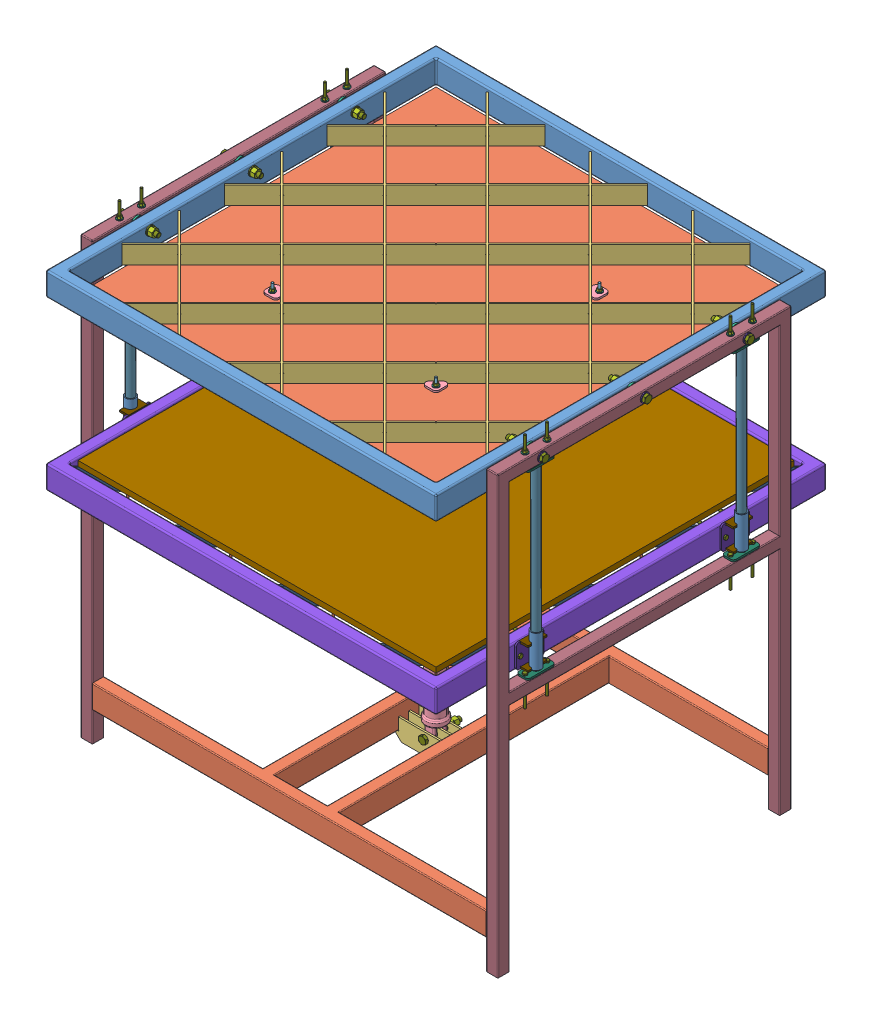
SolidWorks assembly CoolingPress, configuration Default. Lengths in mm.
Overall size (1448 1539 1330).
188 component instances, 26 part files, 122 mates.
Components (placement in the parent):
- Pressing plate upper-1: Pressing plate upper [Default] at origin size (1330 88 1330)
  - Plate frame upper-1: Plate frame upper [Default] at origin size (1330 80 1330)
  - Pressing plate upper-1: Pressing plate upper [Default] x (-1 0 0) z (0 -1 0) size (1220 1220 18)
  - Support structure upper-1: Support structure upper [Default] at origin size (1250 60 1250)
    - Support structure upper-1: Support structure upper [Default] at (0 10 0) size (1250 60 1250)
    - Support structure upper-2: Support structure upper [Default] at (0 70 0) x (-1 0 0) z (0 0 1) size (1250 60 1250)
  - Plywood mount tab-1: Plywood mount tab [Default] at (0 70 0) x (1 0 0) z (0 1 0) size (46.67 46.67 6)
  - Plywood mount tab-2: Plywood mount tab [Default] at (0 70 0) x (0 0 1) z (0 1 0) size (46.67 46.67 6)
  - Plywood mount tab-3: Plywood mount tab [Default] at (0 70 0) x (-1 0 0) z (0 1 0) size (46.67 46.67 6)
  - Plywood mount tab-4: Plywood mount tab [Default] at (0 70 0) x (0 0 -1) z (0 1 0) size (46.67 46.67 6)
  - socket countersunk head screw_iso-1: socket countersunk head screw_iso [ISO 10642 - M8 x 50 - 28N] at (278.7635 -6.96 278.7635) x (0 1 0) z (0 0 1) size (50 15.24 15.24)
  - plain washer 10669 type nl_iso-1: plain washer 10669 type nl_iso [ISO 10669-8.8-N] at (278.7635 17 278.7635) x (0 1 0) z (0 0 1) size (2 20 20)
  - hex nut gradec_iso-1: hex nut gradec_iso [ISO - 4034 - M8 - N] at (278.7635 26.9 278.7635) x (1 0 0) z (0 1 0) size (13 15.01 7.9)
  - plain washer 10669 type nl_iso-2: plain washer 10669 type nl_iso [ISO 10669-8.8-N] at (-278.7635 17 278.7635) x (0 1 0) z (-1 0 0) size (2 20 20)
  - plain washer 10669 type nl_iso-3: plain washer 10669 type nl_iso [ISO 10669-8.8-N] at (-278.7635 17 -278.7635) x (0 1 0) z (0 0 -1) size (2 20 20)
  - plain washer 10669 type nl_iso-4: plain washer 10669 type nl_iso [ISO 10669-8.8-N] at (278.7635 17 -278.7635) x (0 1 0) z (1 0 0) size (2 20 20)
  - hex nut gradec_iso-2: hex nut gradec_iso [ISO - 4034 - M8 - N] at (-278.7635 26.9 278.7635) x (0 0 1) z (0 1 0) size (13 15.01 7.9)
  - hex nut gradec_iso-3: hex nut gradec_iso [ISO - 4034 - M8 - N] at (-278.7635 26.9 -278.7635) x (-1 0 0) z (0 1 0) size (13 15.01 7.9)
  - hex nut gradec_iso-4: hex nut gradec_iso [ISO - 4034 - M8 - N] at (278.7635 26.9 -278.7635) x (0 0 -1) z (0 1 0) size (13 15.01 7.9)
  - socket countersunk head screw_iso-2: socket countersunk head screw_iso [ISO 10642 - M8 x 50 - 28N] at (-278.7635 -6.96 278.7635) x (0 1 0) z (-1 0 0) size (50 15.24 15.24)
  - socket countersunk head screw_iso-3: socket countersunk head screw_iso [ISO 10642 - M8 x 50 - 28N] at (-278.7635 -6.96 -278.7635) x (0 1 0) z (0 0 -1) size (50 15.24 15.24)
  - socket countersunk head screw_iso-4: socket countersunk head screw_iso [ISO 10642 - M8 x 50 - 28N] at (278.7635 -6.96 -278.7635) x (0 1 0) z (1 0 0) size (50 15.24 15.24)
- Pressing plate lower-1: Pressing plate lower [Default] at (0 -490 0) x (-1 0 0) z (0 0 1) size (1330 195 1330)
  - Plate frame lower-1: Plate frame lower [Default] at origin size (1330 80 1330)
  - Pressing plate lower-1: Pressing plate lower [Default] x (-1 0 0) z (0 -1 0) size (1220 1220 18)
  - Support structure lower-1: Support structure lower [Default] at (0 -250.8864 0) x (-1 0 0) z (0 0 1) size (1250 177 1250)
    - Support structure lower a-1: Support structure lower a [Default] at (0 -260.8864 0) x (-1 0 0) z (0 0 1) size (1250 140 1250)
    - Support structure lower b-1: Support structure lower b [Default] at (0 -260.8864 0) x (0 0 -1) z (-1 0 0) size (1250 140 1250)
    - Jack mount-1: Jack mount [Default] at (-15.5563 -260.8864 -15.5563) x (-0.707107 0 0.707107) z (0.707107 0 0.707107) size (75 77 6)
    - Jack mount-2: Jack mount [Default] at (15.5563 -260.8864 15.5563) x (0.707107 0 -0.707107) z (-0.707107 0 -0.707107) size (75 77 6)
- Side frame asm-1: Side frame asm [Default] at (148.9643 90.3004 -178.1954) size (46 1539 1000)
  - Side frame sub asm-1: Side frame sub asm [Default] at (-148.9643 -90.3004 178.1954) size (40 1539 1000)
    - Side frame-1: Side frame [Default] at (665 0 0) x (0 0 -1) z (1 0 0) size (1000 1485 40)
    - Slider rod-1: Slider rod [Default] at (343.5 40 -330) x (1 0 0) z (0 -1 0) size (27 27 620)
    - Slider rod plate-1: Slider rod plate [Default] at (711 -574 -2.5) x (0 0 -1) z (0 -1 0) size (95 40 6)
    - Slider rod plate-2: Slider rod plate [Default] at (711 40 -2.5) x (0 0 -1) z (0 -1 0) size (95 40 6)
    - Slider rod plate-3: Slider rod plate [Default] at (711 -580 2.5) x (0 0 1) z (0 1 0) size (95 40 6)
    - Slider rod plate-4: Slider rod plate [Default] at (711 34 2.5) x (0 0 1) z (0 1 0) size (95 40 6)
    - Slider rod-2: Slider rod [Default] at (343.5 -580 330) x (1 0 0) z (0 1 0) size (27 27 620)
    - hex bolt gradeab_iso-1: hex bolt gradeab_iso [ISO 4014 - M8 x 100 x 100-N] at (691 28.7 -312.5) x (0 1 0) z (0 0 1) size (105.3 15.01 13)
    - hex bolt gradeab_iso-2: hex bolt gradeab_iso [ISO 4014 - M8 x 100 x 100-N] at (691 28.7 -387.5) x (0 1 0) z (0 0 1) size (105.3 15.01 13)
    - hex bolt gradeab_iso-3: hex bolt gradeab_iso [ISO 4014 - M8 x 100 x 100-N] at (691 -568.7 -312.5) x (0 -1 0) z (0 0 1) size (105.3 15.01 13)
    - hex bolt gradeab_iso-4: hex bolt gradeab_iso [ISO 4014 - M8 x 100 x 100-N] at (691 -568.7 -387.5) x (0 -1 0) z (0 0 1) size (105.3 15.01 13)
    - plain washer 10669 type nl_iso-1: plain washer 10669 type nl_iso [ISO 10669-8.8-N] at (691 80 -312.5) x (0 1 0) z (0 0 1) size (2 20 20)
    - plain washer 10669 type nl_iso-2: plain washer 10669 type nl_iso [ISO 10669-8.8-N] at (691 80 -387.5) x (0 1 0) z (0 0 1) size (2 20 20)
    - plain washer 10669 type nl_iso-3: plain washer 10669 type nl_iso [ISO 10669-8.8-N] at (691 -620 -312.5) x (0 -1 0) z (0 0 1) size (2 20 20)
    - plain washer 10669 type nl_iso-4: plain washer 10669 type nl_iso [ISO 10669-8.8-N] at (691 -620 -387.5) x (0 -1 0) z (0 0 1) size (2 20 20)
    - hex nut gradec_iso-1: hex nut gradec_iso [ISO - 4034 - M8 - N] at (691 -629.9 -387.5) x (1 0 0) z (0 -1 0) size (13 15.01 7.9)
    - hex nut gradec_iso-2: hex nut gradec_iso [ISO - 4034 - M8 - N] at (691 -629.9 -312.5) x (1 0 0) z (0 -1 0) size (13 15.01 7.9)
    - hex nut gradec_iso-3: hex nut gradec_iso [ISO - 4034 - M8 - N] at (691 89.9 -312.5) x (1 0 0) z (0 1 0) size (13 15.01 7.9)
    - hex nut gradec_iso-4: hex nut gradec_iso [ISO - 4034 - M8 - N] at (691 89.9 -387.5) x (1 0 0) z (0 1 0) size (13 15.01 7.9)
    - hex bolt gradeab_iso-5: hex bolt gradeab_iso [ISO 4014 - M8 x 100 x 100-N] at (691 28.7 387.5) x (0 1 0) z (0 0 1) size (105.3 15.01 13)
    - hex bolt gradeab_iso-6: hex bolt gradeab_iso [ISO 4014 - M8 x 100 x 100-N] at (691 -568.7 312.5) x (0 -1 0) z (0 0 1) size (105.3 15.01 13)
    - hex bolt gradeab_iso-7: hex bolt gradeab_iso [ISO 4014 - M8 x 100 x 100-N] at (691 -568.7 387.5) x (0 -1 0) z (0 0 1) size (105.3 15.01 13)
    - plain washer 10669 type nl_iso-5: plain washer 10669 type nl_iso [ISO 10669-8.8-N] at (691 80 312.5) x (0 1 0) z (0 0 1) size (2 20 20)
    - plain washer 10669 type nl_iso-6: plain washer 10669 type nl_iso [ISO 10669-8.8-N] at (691 80 387.5) x (0 1 0) z (0 0 1) size (2 20 20)
    - plain washer 10669 type nl_iso-7: plain washer 10669 type nl_iso [ISO 10669-8.8-N] at (691 -620 312.5) x (0 -1 0) z (0 0 1) size (2 20 20)
    - plain washer 10669 type nl_iso-8: plain washer 10669 type nl_iso [ISO 10669-8.8-N] at (691 -620 387.5) x (0 -1 0) z (0 0 1) size (2 20 20)
    - hex nut gradec_iso-5: hex nut gradec_iso [ISO - 4034 - M8 - N] at (691 -622 387.5) x (1 0 0) z (0 1 0) size (13 15.01 7.9)
    - hex nut gradec_iso-6: hex nut gradec_iso [ISO - 4034 - M8 - N] at (691 -622 312.5) x (1 0 0) z (0 1 0) size (13 15.01 7.9)
    - hex nut gradec_iso-7: hex nut gradec_iso [ISO - 4034 - M8 - N] at (691 82 387.5) x (1 0 0) z (0 -1 0) size (13 15.01 7.9)
    - hex bolt gradeab_iso-8: hex bolt gradeab_iso [ISO 4014 - M8 x 100 x 100-N] at (691 28.7 312.5) x (0 1 0) z (0 0 1) size (105.3 15.01 13)
    - hex nut gradec_iso-8: hex nut gradec_iso [ISO - 4034 - M8 - N] at (691 82 312.5) x (1 0 0) z (0 -1 0) size (13 15.01 7.9)
  - Slider bracket-1: Slider bracket [Default] at (-148.9643 -510.7439 178.1954) size (43 110 95)
    - Guide plate coldpress-1: Guide plate coldpress [Default] at (671 -169.5566 -2.5) x (0 0 1) z (-1 0 0) size (95 80 6)
    - Guide bracket-1: Guide bracket [Default] at (665 -169.5566 -697.5) x (0 0 -1) z (1 0 0) size (65 80 31)
    - Slider tube-1: Slider tube [Default] at (665 -149.5566 -697.5) x (0 0 1) z (0 -1 0) size (34 34 110)
  - Slider bracket-2: Slider bracket [Default] at (-148.9643 -510.7439 878.1954) size (43 110 95)
    - Guide plate coldpress-1: Guide plate coldpress [Default] at (671 -169.5566 -2.5) x (0 0 1) z (-1 0 0) size (95 80 6)
    - Guide bracket-1: Guide bracket [Default] at (665 -169.5566 -697.5) x (0 0 -1) z (1 0 0) size (65 80 31)
    - Slider tube-1: Slider tube [Default] at (665 -149.5566 -697.5) x (0 0 1) z (0 -1 0) size (34 34 110)
- Side frame asm-2: Side frame asm [Default] at (-148.9643 90.3004 178.1954) x (-1 0 0) z (0 0 -1) size (46 1539 1000)
  - Side frame sub asm-1: Side frame sub asm [Default] at (-148.9643 -90.3004 178.1954) size (40 1539 1000)
    - Side frame-1: Side frame [Default] at (665 0 0) x (0 0 -1) z (1 0 0) size (1000 1485 40)
    - Slider rod-1: Slider rod [Default] at (343.5 40 -330) x (1 0 0) z (0 -1 0) size (27 27 620)
    - Slider rod plate-1: Slider rod plate [Default] at (711 -574 -2.5) x (0 0 -1) z (0 -1 0) size (95 40 6)
    - Slider rod plate-2: Slider rod plate [Default] at (711 40 -2.5) x (0 0 -1) z (0 -1 0) size (95 40 6)
    - Slider rod plate-3: Slider rod plate [Default] at (711 -580 2.5) x (0 0 1) z (0 1 0) size (95 40 6)
    - Slider rod plate-4: Slider rod plate [Default] at (711 34 2.5) x (0 0 1) z (0 1 0) size (95 40 6)
    - Slider rod-2: Slider rod [Default] at (343.5 -580 330) x (1 0 0) z (0 1 0) size (27 27 620)
    - hex bolt gradeab_iso-1: hex bolt gradeab_iso [ISO 4014 - M8 x 100 x 100-N] at (691 28.7 -312.5) x (0 1 0) z (0 0 1) size (105.3 15.01 13)
    - hex bolt gradeab_iso-2: hex bolt gradeab_iso [ISO 4014 - M8 x 100 x 100-N] at (691 28.7 -387.5) x (0 1 0) z (0 0 1) size (105.3 15.01 13)
    - hex bolt gradeab_iso-3: hex bolt gradeab_iso [ISO 4014 - M8 x 100 x 100-N] at (691 -568.7 -312.5) x (0 -1 0) z (0 0 1) size (105.3 15.01 13)
    - hex bolt gradeab_iso-4: hex bolt gradeab_iso [ISO 4014 - M8 x 100 x 100-N] at (691 -568.7 -387.5) x (0 -1 0) z (0 0 1) size (105.3 15.01 13)
    - plain washer 10669 type nl_iso-1: plain washer 10669 type nl_iso [ISO 10669-8.8-N] at (691 80 -312.5) x (0 1 0) z (0 0 1) size (2 20 20)
    - plain washer 10669 type nl_iso-2: plain washer 10669 type nl_iso [ISO 10669-8.8-N] at (691 80 -387.5) x (0 1 0) z (0 0 1) size (2 20 20)
    - plain washer 10669 type nl_iso-3: plain washer 10669 type nl_iso [ISO 10669-8.8-N] at (691 -620 -312.5) x (0 -1 0) z (0 0 1) size (2 20 20)
    - plain washer 10669 type nl_iso-4: plain washer 10669 type nl_iso [ISO 10669-8.8-N] at (691 -620 -387.5) x (0 -1 0) z (0 0 1) size (2 20 20)
    - hex nut gradec_iso-1: hex nut gradec_iso [ISO - 4034 - M8 - N] at (691 -629.9 -387.5) x (1 0 0) z (0 -1 0) size (13 15.01 7.9)
    - hex nut gradec_iso-2: hex nut gradec_iso [ISO - 4034 - M8 - N] at (691 -629.9 -312.5) x (1 0 0) z (0 -1 0) size (13 15.01 7.9)
    - hex nut gradec_iso-3: hex nut gradec_iso [ISO - 4034 - M8 - N] at (691 89.9 -312.5) x (1 0 0) z (0 1 0) size (13 15.01 7.9)
    - hex nut gradec_iso-4: hex nut gradec_iso [ISO - 4034 - M8 - N] at (691 89.9 -387.5) x (1 0 0) z (0 1 0) size (13 15.01 7.9)
    - hex bolt gradeab_iso-5: hex bolt gradeab_iso [ISO 4014 - M8 x 100 x 100-N] at (691 28.7 387.5) x (0 1 0) z (0 0 1) size (105.3 15.01 13)
    - hex bolt gradeab_iso-6: hex bolt gradeab_iso [ISO 4014 - M8 x 100 x 100-N] at (691 -568.7 312.5) x (0 -1 0) z (0 0 1) size (105.3 15.01 13)
    - hex bolt gradeab_iso-7: hex bolt gradeab_iso [ISO 4014 - M8 x 100 x 100-N] at (691 -568.7 387.5) x (0 -1 0) z (0 0 1) size (105.3 15.01 13)
    - plain washer 10669 type nl_iso-5: plain washer 10669 type nl_iso [ISO 10669-8.8-N] at (691 80 312.5) x (0 1 0) z (0 0 1) size (2 20 20)
    - plain washer 10669 type nl_iso-6: plain washer 10669 type nl_iso [ISO 10669-8.8-N] at (691 80 387.5) x (0 1 0) z (0 0 1) size (2 20 20)
    - plain washer 10669 type nl_iso-7: plain washer 10669 type nl_iso [ISO 10669-8.8-N] at (691 -620 312.5) x (0 -1 0) z (0 0 1) size (2 20 20)
    - plain washer 10669 type nl_iso-8: plain washer 10669 type nl_iso [ISO 10669-8.8-N] at (691 -620 387.5) x (0 -1 0) z (0 0 1) size (2 20 20)
    - hex nut gradec_iso-5: hex nut gradec_iso [ISO - 4034 - M8 - N] at (691 -622 387.5) x (1 0 0) z (0 1 0) size (13 15.01 7.9)
    - hex nut gradec_iso-6: hex nut gradec_iso [ISO - 4034 - M8 - N] at (691 -622 312.5) x (1 0 0) z (0 1 0) size (13 15.01 7.9)
    - hex nut gradec_iso-7: hex nut gradec_iso [ISO - 4034 - M8 - N] at (691 82 387.5) x (1 0 0) z (0 -1 0) size (13 15.01 7.9)
    - hex bolt gradeab_iso-8: hex bolt gradeab_iso [ISO 4014 - M8 x 100 x 100-N] at (691 28.7 312.5) x (0 1 0) z (0 0 1) size (105.3 15.01 13)
    - hex nut gradec_iso-8: hex nut gradec_iso [ISO - 4034 - M8 - N] at (691 82 312.5) x (1 0 0) z (0 -1 0) size (13 15.01 7.9)
  - Slider bracket-1: Slider bracket [Default] at (-148.9643 -510.7439 178.1954) size (43 110 95)
    - Guide plate coldpress-1: Guide plate coldpress [Default] at (671 -169.5566 -2.5) x (0 0 1) z (-1 0 0) size (95 80 6)
    - Guide bracket-1: Guide bracket [Default] at (665 -169.5566 -697.5) x (0 0 -1) z (1 0 0) size (65 80 31)
    - Slider tube-1: Slider tube [Default] at (665 -149.5566 -697.5) x (0 0 1) z (0 -1 0) size (34 34 110)
  - Slider bracket-2: Slider bracket [Default] at (-148.9643 -510.7439 878.1954) size (43 110 95)
    - Guide plate coldpress-1: Guide plate coldpress [Default] at (671 -169.5566 -2.5) x (0 0 1) z (-1 0 0) size (95 80 6)
    - Guide bracket-1: Guide bracket [Default] at (665 -169.5566 -697.5) x (0 0 -1) z (1 0 0) size (65 80 31)
    - Slider tube-1: Slider tube [Default] at (665 -149.5566 -697.5) x (0 0 1) z (0 -1 0) size (34 34 110)
- Bottom frame asm-1: Bottom frame asm [Default] at (-144.5589 173.4267 15.9564) size (1342 110 1000)
  - Part2-1: Part2 [Default] at (144.5589 -1478.4267 -15.9564) x (-1 0 0) z (0 -1 0) size (1342 1000 80)
  - Jack plate lower-1: Jack plate lower [Default] at origin size (200 70 6)
  - Jack plate lower-2: Jack plate lower [Default] at (0 0 35) size (200 70 6)
  - Jack plate lower-4: Jack plate lower [Default] at (0 0 -35) size (200 70 6)
- Jack asm-2: Jack asm [Default] at (0 -1250 0) x (0 0 1) z (-1 0 0) size (71.65 655 71.65) (flexible)
  - Cylinder-1: Cylinder [Default] at origin size (71.65 615 71.65)
  - Jack rod-1: Jack rod [Default] at (-0.0001 55 -0.0001) x (0.707107 0 0.707107) z (-0.707107 0 0.707107) size (28 550 28)
- Spacer-4: Spacer [Default] at (-671 0 0) x (0 0 -1) z (1 0 0) size (40 40 6)
- Spacer-5: Spacer [Default] at (-665 0 -350) x (0 0 1) z (-1 0 0) size (40 40 6)
- Spacer-6: Spacer [Default] at (-671 0 700) x (0 0 -1) z (1 0 0) size (40 40 6)
- Spacer-1: Spacer [Default] at (665 0 0) x (0 0 -1) z (1 0 0) size (40 40 6)
- Spacer-2: Spacer [Default] at (671 0 -350) x (0 0 1) z (-1 0 0) size (40 40 6)
- Spacer-3: Spacer [Default] at (665 0 700) x (0 0 -1) z (1 0 0) size (40 40 6)
- hex bolt gradeab_iso-3: hex bolt gradeab_iso [ISO 4014 - M8 x 100 x 100-N] at (676.3 -530 -314.5) x (-1 0 0) z (0 0.924225 0.381849) size (105.3 15.01 13)
- hex bolt gradeab_iso-4: hex bolt gradeab_iso [ISO 4014 - M8 x 100 x 100-N] at (676.3 -530 -385.5) x (-1 0 0) z (0 0.924225 0.381849) size (105.3 15.01 13)
- hex bolt gradeab_iso-8: hex bolt gradeab_iso [ISO 4014 - M16 x 120 x 38-N] at (724 60 -350) x (-1 0 0) z (0 0.981514 -0.191391) size (130 27.71 24)
- hex bolt gradeab_iso-9: hex bolt gradeab_iso [ISO 4014 - M16 x 120 x 38-N] at (724 60 0) x (-1 0 0) z (0 -0.958722 -0.284344) size (130 27.71 24)
- hex bolt gradeab_iso-10: hex bolt gradeab_iso [ISO 4014 - M16 x 120 x 38-N] at (0 -1285 48) x (0 0 -1) z (1 0 0) size (130 27.71 24)
- hex bolt gradeab_iso-11: hex bolt gradeab_iso [ISO 4014 - M16 x 120 x 38-N] at (22.6275 -665 22.6274) x (-0.707107 0 -0.707107) z (0.707107 0 -0.707107) size (130 27.71 24)
- plain washer 10669 type nl_iso-5: plain washer 10669 type nl_iso [ISO 10669-8.8-N] at (625 -530 -314.5) x (-1 0 0) z (0 0.924225 0.381849) size (2 20 20)
- plain washer 10669 type nl_iso-6: plain washer 10669 type nl_iso [ISO 10669-8.8-N] at (625 -530 -385.5) x (-1 0 0) z (0 0.924225 0.381849) size (2 20 20)
- plain washer normal grade a_iso-1: plain washer normal grade a_iso [Washer ISO 7089 - 16] at (625 60 -350) size (3 30 30)
- plain washer normal grade a_iso-2: plain washer normal grade a_iso [Washer ISO 7089 - 16] at (625 60 0) size (3 30 30)
- hex nut gradec_iso-1: hex nut gradec_iso [ISO - 4034 - M16 - N] at (606.1 60 -350) x (0 0 1) z (-1 0 0) size (24 27.71 15.9)
- hex nut gradec_iso-2: hex nut gradec_iso [ISO - 4034 - M16 - N] at (606.1 60 0) x (0 0 1) z (-1 0 0) size (24 27.71 15.9)
- hex nut gradec_iso-3: hex nut gradec_iso [ISO - 4034 - M16 - N] at (-26.7994 -665 -26.7993) x (-0.707107 0 0.707107) z (-0.707107 0 -0.707107) size (24 27.71 15.9)
- hex nut gradec_iso-4: hex nut gradec_iso [ISO - 4034 - M16 - N] at (-38.0424 -665 -38.0423) x (-0.707107 0 0.707107) z (-0.707107 0 -0.707107) size (24 27.71 15.9)
- hex nut gradec_iso-5: hex nut gradec_iso [ISO - 4034 - M16 - N] at (0 -1285 -53.9) x (0.923728 0.383049 0) z (0 0 -1) size (24 27.71 15.9)
- hex nut gradec_iso-6: hex nut gradec_iso [ISO - 4034 - M16 - N] at (0 -1285 -69.8) x (0.923728 0.383049 0) z (0 0 -1) size (24 27.71 15.9)
- hex nut gradec_iso-11: hex nut gradec_iso [ISO - 4034 - M8 - N] at (615.1 -530 -314.5) x (0 0 1) z (-1 0 0) size (13 15.01 7.9)
- hex nut gradec_iso-12: hex nut gradec_iso [ISO - 4034 - M8 - N] at (615.1 -530 -385.5) x (0 0 1) z (-1 0 0) size (13 15.01 7.9)
- hex nut gradec_iso-13: hex nut gradec_iso [ISO - 4034 - M8 - N] at (607.2 -530 -314.5) x (0 0 1) z (-1 0 0) size (13 15.01 7.9)
- hex nut gradec_iso-14: hex nut gradec_iso [ISO - 4034 - M8 - N] at (607.2 -530 -385.5) x (0 0 1) z (-1 0 0) size (13 15.01 7.9)
- plain washer normal grade c_iso-1: plain washer normal grade c_iso [Washer ISO 7091 - 16] at (711 60 -350) x (-1 0 0) z (0 0.924225 0.381849) size (3 30 30)
- plain washer normal grade c_iso-2: plain washer normal grade c_iso [Washer ISO 7091 - 16] at (711 60 0) x (-1 0 0) z (0 0.924225 0.381849) size (3 30 30)
- hex bolt gradeab_iso-13: hex bolt gradeab_iso [ISO 4014 - M16 x 120 x 38-N] at (724 60 350) x (-1 0 0) z (0 -0.981514 -0.191391) size (130 27.71 24)
- hex nut gradec_iso-15: hex nut gradec_iso [ISO - 4034 - M16 - N] at (622 60 350) x (0 0 -1) z (1 0 0) size (24 27.71 15.9)
- plain washer normal grade a_iso-3: plain washer normal grade a_iso [Washer ISO 7089 - 16] at (625 60 350) size (3 30 30)
- hex bolt gradeab_iso-14: hex bolt gradeab_iso [ISO 4014 - M16 x 120 x 38-N] at (-724 60 -350) x (1 0 0) z (0 -0.981514 0.191391) size (130 27.71 24)
- hex nut gradec_iso-16: hex nut gradec_iso [ISO - 4034 - M16 - N] at (-622 60 -350) x (0 0 1) z (-1 0 0) size (24 27.71 15.9)
- plain washer normal grade a_iso-4: plain washer normal grade a_iso [Washer ISO 7089 - 16] at (-625 60 -350) x (-1 0 0) z (0 0 -1) size (3 30 30)
- hex bolt gradeab_iso-15: hex bolt gradeab_iso [ISO 4014 - M16 x 120 x 38-N] at (-724 60 350) x (1 0 0) z (0 0.981514 0.191391) size (130 27.71 24)
- hex nut gradec_iso-17: hex nut gradec_iso [ISO - 4034 - M16 - N] at (-606.1 60 350) x (0 0 -1) z (1 0 0) size (24 27.71 15.9)
- plain washer normal grade a_iso-5: plain washer normal grade a_iso [Washer ISO 7089 - 16] at (-625 60 350) x (-1 0 0) z (0 0 -1) size (3 30 30)
- plain washer normal grade a_iso-6: plain washer normal grade a_iso [Washer ISO 7089 - 16] at (-625 60 0) x (-1 0 0) z (0 0 -1) size (3 30 30)
- hex bolt gradeab_iso-16: hex bolt gradeab_iso [ISO 4014 - M16 x 120 x 38-N] at (-724 60 0) x (1 0 0) z (0 0.958722 0.284344) size (130 27.71 24)
- hex nut gradec_iso-18: hex nut gradec_iso [ISO - 4034 - M16 - N] at (-622 60 0) x (0 0 1) z (-1 0 0) size (24 27.71 15.9)
- hex bolt gradeab_iso-17: hex bolt gradeab_iso [ISO 4014 - M8 x 100 x 100-N] at (676.3 -530 314.5) x (-1 0 0) z (0 -0.924225 0.381849) size (105.3 15.01 13)
- hex nut gradec_iso-19: hex nut gradec_iso [ISO - 4034 - M8 - N] at (615.1 -530 314.5) x (0 0 -1) z (1 0 0) size (13 15.01 7.9)
- hex nut gradec_iso-20: hex nut gradec_iso [ISO - 4034 - M8 - N] at (623 -530 314.5) x (0 0 -1) z (1 0 0) size (13 15.01 7.9)
- plain washer 10669 type nl_iso-7: plain washer 10669 type nl_iso [ISO 10669-8.8-N] at (625 -530 314.5) x (-1 0 0) z (0 -0.924225 0.381849) size (2 20 20)
- hex bolt gradeab_iso-18: hex bolt gradeab_iso [ISO 4014 - M8 x 100 x 100-N] at (676.3 -530 385.5) x (-1 0 0) z (0 -0.924225 0.381849) size (105.3 15.01 13)
- hex nut gradec_iso-21: hex nut gradec_iso [ISO - 4034 - M8 - N] at (615.1 -530 385.5) x (0 0 -1) z (1 0 0) size (13 15.01 7.9)
- hex nut gradec_iso-22: hex nut gradec_iso [ISO - 4034 - M8 - N] at (623 -530 385.5) x (0 0 -1) z (1 0 0) size (13 15.01 7.9)
- plain washer 10669 type nl_iso-8: plain washer 10669 type nl_iso [ISO 10669-8.8-N] at (625 -530 385.5) x (-1 0 0) z (0 -0.924225 0.381849) size (2 20 20)
- hex bolt gradeab_iso-19: hex bolt gradeab_iso [ISO 4014 - M8 x 100 x 100-N] at (-676.3 -530 -314.5) x (1 0 0) z (0 -0.924225 -0.381849) size (105.3 15.01 13)
- hex nut gradec_iso-23: hex nut gradec_iso [ISO - 4034 - M8 - N] at (-615.1 -530 -314.5) x (0 0 1) z (-1 0 0) size (13 15.01 7.9)
- hex nut gradec_iso-24: hex nut gradec_iso [ISO - 4034 - M8 - N] at (-623 -530 -314.5) x (0 0 1) z (-1 0 0) size (13 15.01 7.9)
- plain washer 10669 type nl_iso-9: plain washer 10669 type nl_iso [ISO 10669-8.8-N] at (-625 -530 -314.5) x (1 0 0) z (0 -0.924225 -0.381849) size (2 20 20)
- hex bolt gradeab_iso-20: hex bolt gradeab_iso [ISO 4014 - M8 x 100 x 100-N] at (-676.3 -530 -385.5) x (1 0 0) z (0 -0.924225 -0.381849) size (105.3 15.01 13)
- hex nut gradec_iso-25: hex nut gradec_iso [ISO - 4034 - M8 - N] at (-615.1 -530 -385.5) x (0 0 1) z (-1 0 0) size (13 15.01 7.9)
- hex nut gradec_iso-26: hex nut gradec_iso [ISO - 4034 - M8 - N] at (-623 -530 -385.5) x (0 0 1) z (-1 0 0) size (13 15.01 7.9)
- plain washer 10669 type nl_iso-10: plain washer 10669 type nl_iso [ISO 10669-8.8-N] at (-625 -530 -385.5) x (1 0 0) z (0 -0.924225 -0.381849) size (2 20 20)
- hex bolt gradeab_iso-21: hex bolt gradeab_iso [ISO 4014 - M8 x 100 x 100-N] at (-676.3 -530 385.5) x (1 0 0) z (0 0.924225 -0.381849) size (105.3 15.01 13)
- hex nut gradec_iso-27: hex nut gradec_iso [ISO - 4034 - M8 - N] at (-607.2 -530 385.5) x (0 0 -1) z (1 0 0) size (13 15.01 7.9)
- hex nut gradec_iso-28: hex nut gradec_iso [ISO - 4034 - M8 - N] at (-615.1 -530 385.5) x (0 0 -1) z (1 0 0) size (13 15.01 7.9)
- plain washer 10669 type nl_iso-11: plain washer 10669 type nl_iso [ISO 10669-8.8-N] at (-625 -530 385.5) x (1 0 0) z (0 0.924225 -0.381849) size (2 20 20)
- hex bolt gradeab_iso-22: hex bolt gradeab_iso [ISO 4014 - M8 x 100 x 100-N] at (-676.3 -530 314.5) x (1 0 0) z (0 0.924225 -0.381849) size (105.3 15.01 13)
- hex nut gradec_iso-29: hex nut gradec_iso [ISO - 4034 - M8 - N] at (-607.2 -530 314.5) x (0 0 -1) z (1 0 0) size (13 15.01 7.9)
- hex nut gradec_iso-30: hex nut gradec_iso [ISO - 4034 - M8 - N] at (-615.1 -530 314.5) x (0 0 -1) z (1 0 0) size (13 15.01 7.9)
- plain washer 10669 type nl_iso-12: plain washer 10669 type nl_iso [ISO 10669-8.8-N] at (-625 -530 314.5) x (1 0 0) z (0 0.924225 -0.381849) size (2 20 20)
- plain washer normal grade c_iso-3: plain washer normal grade c_iso [Washer ISO 7091 - 16] at (711 60 350) x (-1 0 0) z (0 -0.924225 0.381849) size (3 30 30)
- plain washer normal grade c_iso-4: plain washer normal grade c_iso [Washer ISO 7091 - 16] at (-711 60 350) x (1 0 0) z (0 0.924225 -0.381849) size (3 30 30)
- plain washer normal grade c_iso-5: plain washer normal grade c_iso [Washer ISO 7091 - 16] at (-711 60 0) x (1 0 0) z (0 -0.924225 -0.381849) size (3 30 30)
- plain washer normal grade c_iso-6: plain washer normal grade c_iso [Washer ISO 7091 - 16] at (-711 60 -350) x (1 0 0) z (0 -0.924225 -0.381849) size (3 30 30)
Mates (geometry in assembly coordinates):
- Parallel2: parallel: plane of Pressing plate lower-1/Plate frame lower-1 through (0 -490 0) normal (0 -1 0); plane of assembly through (0 0 0) normal (0 1 0)
- Coincident3: coincident: plane of Pressing plate lower-1/Plate frame lower-1 through (0 -490 0) normal (0 0 1); plane of assembly through (0 0 0) normal (0 0 1)
- Coincident4: coincident: plane of Pressing plate lower-1/Plate frame lower-1 through (0 -490 0) normal (-1 0 0); plane of assembly through (0 0 0) normal (1 0 0)
- InPlace12: in place: plane of ? through (-671 0 460) normal (0 0 -1); plane of ? through (0 0 460) normal (0 0 -1); moOrthogonalPlaneRef_w of ? through (-671 0 460) normal (0 0 -1); plane of ? through (0 0 460) normal (0 1 0); plane of ? through (-671 0 460) normal (0 0 -1); plane of ? through (0 0 460) normal (-1 0 0); plane of ? through (-671 0 460) normal (0 0 -1); unknown of ?
- Coincident22: coincident: plane of ?; plane of ?
- Coincident23: coincident: moOrthogonalPlaneRef_w of ? through (-717 0 460) normal (0 1 0); plane of ? through (-717 0 460) normal (0 1 0)
- Coincident24: coincident: moOrthogonalPlaneRef_w of ? through (-717 0 460) normal (1 0 0); plane of ? through (-717 0 460) normal (-1 0 0)
- InPlace13: in place: plane of Pressing plate upper-1/Plate frame upper-1 through (0 0 0) normal (0 0 1); plane of Pressing plate upper-1/Plate frame upper-1 through (0 0 0) normal (0 1 0); plane of Pressing plate upper-1/Plate frame upper-1 through (0 0 0) normal (1 0 0); unknown of Pressing plate upper-1/Plate frame upper-1
- Coincident21: coincident: plane of ?; plane of assembly
- Coincident22: coincident: plane of Pressing plate upper-1/Plate frame upper-1 through (0 0 0) normal (0 1 0)
- Coincident23: coincident: plane of Pressing plate upper-1/Plate frame upper-1 through (0 0 0) normal (1 0 0)
- Parallel7: parallel: plane of Pressing plate lower-1/Support structure lower-1/Support structure lower b-1 through (0 -500 0) normal (0 -1 0); plane of assembly through (0 0 0) normal (0 1 0)
- Coincident38: coincident: plane of Pressing plate lower-1/Support structure lower-1/Support structure lower b-1 through (0 -500 0) normal (-1 0 0); plane of assembly through (0 0 0) normal (1 0 0)
- Coincident39: coincident: plane of Pressing plate lower-1/Support structure lower-1/Support structure lower b-1 through (0 -500 0) normal (0 0 -1); plane of assembly through (0 0 0) normal (0 0 1)
- Parallel8: parallel: plane of Pressing plate lower-1/Support structure lower-1/Support structure lower a-1 through (0 -500 0) normal (0 -1 0); plane of assembly through (0 0 0) normal (0 1 0)
- Coincident41: coincident: plane of Pressing plate lower-1/Support structure lower-1/Support structure lower a-1 through (0 -500 0) normal (0 0 1); plane of assembly through (0 0 0) normal (0 0 1)
- Coincident42: coincident: plane of Pressing plate lower-1/Support structure lower-1/Support structure lower a-1 through (0 -500 0) normal (-1 0 0); plane of assembly through (0 0 0) normal (1 0 0)
- Coincident53: coincident: plane of Pressing plate upper-1/Plate frame upper-1 through (0 80 0) normal (0 1 0); plane of Side frame asm-1/Side frame sub asm-1/Side frame-1 through (711 80 0) normal (0 1 0)
- Coincident54: coincident: plane of Pressing plate lower-1/Plate frame lower-1 through (665 -570 -665) normal (1 0 0); plane of Side frame asm-1/Slider bracket-1/Guide plate coldpress-1 through (665 -500 -312.5) normal (-1 0 0)
- Coincident55: coincident: plane of Pressing plate lower-1/Plate frame lower-1 through (0 -490 0) normal (0 1 0); plane of Side frame asm-1/Slider bracket-1/Guide plate coldpress-1 through (665 -490 -317.5) normal (0 1 0)
- Coincident57: coincident: plane of Pressing plate lower-1/Plate frame lower-1 through (665 -570 -665) normal (1 0 0); plane of Side frame asm-1/Slider bracket-1/Guide bracket-1 through (665 -590 -697.5) normal (-1 0 0)
- Coincident58: coincident: plane of Pressing plate lower-1/Plate frame lower-1 through (0 -490 0) normal (0 1 0); plane of Side frame asm-1/Slider bracket-1/Guide bracket-1 through (776.2763 -490 -382.5) normal (0 1 0)
- LimitDistance1: limit distance = 474 mm: plane of Pressing plate lower-1/Pressing plate lower-1 through (0 -482 0) normal (0 1 0); plane of Pressing plate upper-1/Pressing plate upper-1 through (0 -8 0) normal (0 -1 0)
- Coincident59: coincident: plane of Side frame asm-2/Side frame sub asm-1/Side frame-1 through (-711 0 500) normal (0 0 1); plane of Bottom frame asm-1/Part2-1 through (-671 -1225 500) normal (0 0 1)
- Distance3: distance = 100 mm: plane of Bottom frame asm-1/Part2-1 through (0 -1305 0) normal (0 -1 0); plane of Side frame asm-2/Side frame sub asm-1/Side frame-1 through (-711 -1405 0) normal (0 -1 0)
- Coincident61: coincident: plane of Side frame asm-1/Side frame sub asm-1/Side frame-1 through (671 0 0) normal (-1 0 0); plane of Bottom frame asm-1/Part2-1 through (671 -1225 500) normal (1 0 0)
- Coincident62: coincident: line of Jack asm-2/Cylinder-1 through (527.0226 0 -1255.0679) axis (0 0 1)
- Concentric8: concentric: cylinder of Pressing plate lower-1/Support structure lower-1/Jack mount-2 through (-64.6928 -665 -64.6929) axis (0.707107 0 0.707107) radius 9; cylinder of Jack asm-2/Jack rod-1 through (9.8996 -665 9.8994) axis (-0.707107 0 -0.707107) radius 8
- Parallel11: parallel: plane of Bottom frame asm-1/Jack plate lower-1 through (90 -1305 3) normal (0 0 1); plane of Jack asm-2/Cylinder-1 through (-17.5 -1300 -11) normal (0 0 1)
- InPlace14: in place: plane of Pressing plate upper-1/Plate frame upper-1 through (665 80 -665) normal (1 0 0); plane of ? through (665 0 0) normal (1 0 0); plane of Pressing plate upper-1/Plate frame upper-1 through (665 80 -665) normal (1 0 0); plane of ? through (665 0 0) normal (0 1 0); plane of Pressing plate upper-1/Plate frame upper-1 through (665 80 -665) normal (1 0 0); plane of ? through (665 0 0) normal (0 0 -1); plane of Pressing plate upper-1/Plate frame upper-1 through (665 80 -665) normal (1 0 0); unknown of ?
- Coincident63: coincident: plane of Pressing plate upper-1/Plate frame upper-1; plane of Spacer-1
- Coincident64: coincident: moOrthogonalPlaneRef_w of Pressing plate upper-1/Plate frame upper-1 through (665 0 0) normal (0 1 0); plane of Spacer-1 through (665 0 0) normal (0 1 0)
- Coincident65: coincident: moOrthogonalPlaneRef_w of Pressing plate upper-1/Plate frame upper-1 through (665 0 0) normal (0 0 1); plane of Spacer-1 through (665 0 0) normal (0 0 -1)
- Coincident66: coincident: plane of Pressing plate upper-1/Plate frame upper-1 through (665 80 -665) normal (1 0 0); plane of Spacer-2 through (665 60 0) normal (-1 0 0)
- Concentric9: concentric: cylinder of Side frame asm-1/Side frame sub asm-1/Side frame-1 through (671 60 0) axis (1 0 0) radius 9; cylinder of Spacer-2 through (665 60 0) axis (1 0 0) radius 8.5
- Concentric10: concentric: cylinder of Side frame asm-1/Side frame sub asm-1/Side frame-1 through (671 60 350) axis (1 0 0) radius 9; cylinder of Spacer-3 through (671 60 350) axis (-1 0 0) radius 8.5
- Coincident67: coincident: plane of Side frame asm-1/Side frame sub asm-1/Side frame-1 through (671 0 0) normal (-1 0 0); plane of Spacer-3 through (671 60 350) normal (1 0 0)
- Concentric11: concentric: cylinder of Side frame asm-1/Side frame sub asm-1/Slider rod plate-2 through (691 34 -312.5) axis (0 1 0) radius 4.25; cylinder of Side frame asm-1/Side frame sub asm-1/hex bolt gradeab_iso-1 through (691 28.7 -312.5) axis (0 -1 0) radius 6.5
- Coincident68: coincident: plane of Side frame asm-1/Side frame sub asm-1/Slider rod plate-2 through (711 34 -2.5) normal (0 -1 0); plane of Side frame asm-1/Side frame sub asm-1/hex bolt gradeab_iso-1 through (683.4944 34 -312.5) normal (0 1 0)
- Concentric12: concentric: cylinder of Side frame asm-1/Side frame sub asm-1/Slider rod plate-2 through (691 34 -387.5) axis (0 1 0) radius 4.25; cylinder of Side frame asm-1/Side frame sub asm-1/hex bolt gradeab_iso-2 through (691 28.7 -387.5) axis (0 -1 0) radius 6.5
- Coincident69: coincident: plane of Side frame asm-1/Side frame sub asm-1/Slider rod plate-2 through (711 34 -2.5) normal (0 -1 0); plane of Side frame asm-1/Side frame sub asm-1/hex bolt gradeab_iso-2 through (683.4944 34 -387.5) normal (0 1 0)
- Concentric13: concentric: cylinder of Side frame asm-1/Slider bracket-1/Guide plate coldpress-1 through (665 -530 -314.5) axis (1 0 0) radius 4.25; cylinder of hex bolt gradeab_iso-3 through (676.3 -530 -314.5) axis (1 0 0) radius 6.5
- Coincident70: coincident: plane of Side frame asm-1/Slider bracket-1/Guide plate coldpress-1 through (671 -500 -312.5) normal (1 0 0); plane of hex bolt gradeab_iso-3 through (671 -532.866 -307.5632) normal (-1 0 0)
- Concentric14: concentric: cylinder of Side frame asm-1/Slider bracket-1/Guide plate coldpress-1 through (665 -530 -385.5) axis (1 0 0) radius 4.25; cylinder of hex bolt gradeab_iso-4 through (676.3 -530 -385.5) axis (1 0 0) radius 6.5
- Coincident71: coincident: plane of Side frame asm-1/Slider bracket-1/Guide plate coldpress-1 through (671 -500 -312.5) normal (1 0 0); plane of hex bolt gradeab_iso-4 through (671 -532.866 -378.5632) normal (-1 0 0)
- Concentric17: concentric: cylinder of Side frame asm-1/Side frame sub asm-1/Slider rod plate-4 through (691 40 387.5) axis (0 -1 0) radius 4.25; cylinder of Side frame asm-1/Side frame sub asm-1/hex bolt gradeab_iso-5 through (691 28.7 387.5) axis (0 -1 0) radius 6.5
- Coincident74: coincident: plane of Side frame asm-1/Side frame sub asm-1/Slider rod plate-4 through (711 34 2.5) normal (0 -1 0); plane of Side frame asm-1/Side frame sub asm-1/hex bolt gradeab_iso-5 through (683.4944 34 387.5) normal (0 1 0)
- Concentric18: concentric: cylinder of Side frame asm-1/Side frame sub asm-1/Side frame-1 through (671 60 -350) axis (1 0 0) radius 9; cylinder of hex bolt gradeab_iso-8 through (724 60 -350) axis (1 0 0) radius 12
- Concentric19: concentric: cylinder of Side frame asm-1/Side frame sub asm-1/Side frame-1 through (671 60 0) axis (1 0 0) radius 9; cylinder of hex bolt gradeab_iso-9 through (724 60 0) axis (1 0 0) radius 12
- Concentric20: concentric: cylinder of Bottom frame asm-1/Jack plate lower-2 through (0 -1285 32) axis (0 0 1) radius 9; cylinder of hex bolt gradeab_iso-10 through (0 -1285 48) axis (0 0 1) radius 12
- Coincident77: coincident: plane of Bottom frame asm-1/Jack plate lower-2 through (90 -1305 38) normal (0 0 1); plane of hex bolt gradeab_iso-10 through (0 -1271.1436 38) normal (0 0 -1)
- Concentric21: concentric: cylinder of Pressing plate lower-1/Support structure lower-1/Jack mount-2 through (-64.6928 -665 -64.6929) axis (0.707107 0 0.707107) radius 9; cylinder of hex bolt gradeab_iso-11 through (22.6275 -665 22.6274) axis (0.707107 0 0.707107) radius 12
- Coincident78: coincident: plane of Pressing plate lower-1/Support structure lower-1/Jack mount-2 through (15.5563 -500 15.5563) normal (0.707107 0 0.707107); plane of hex bolt gradeab_iso-11 through (15.5564 -651.1436 15.5563) normal (-0.707107 0 -0.707107)
- Concentric22: concentric: cylinder of Side frame asm-1/Side frame sub asm-1/Side frame-1 through (691 -1405 -312.5) axis (0 1 0) radius 5; cylinder of Side frame asm-1/Side frame sub asm-1/plain washer 10669 type nl_iso-1 through (691 82 -312.5) axis (0 -1 0) radius 4.4
- Coincident79: coincident: plane of Side frame asm-1/Side frame sub asm-1/Side frame-1 through (711 80 0) normal (0 1 0); plane of Side frame asm-1/Side frame sub asm-1/plain washer 10669 type nl_iso-1 through (691 80 -312.5) normal (0 -1 0)
- Concentric23: concentric: cylinder of Side frame asm-1/Side frame sub asm-1/Side frame-1 through (691 -1405 -387.5) axis (0 1 0) radius 5; cylinder of Side frame asm-1/Side frame sub asm-1/plain washer 10669 type nl_iso-2 through (691 82 -387.5) axis (0 -1 0) radius 4.4
- Coincident80: coincident: plane of Side frame asm-1/Side frame sub asm-1/Side frame-1 through (711 80 0) normal (0 1 0); plane of Side frame asm-1/Side frame sub asm-1/plain washer 10669 type nl_iso-2 through (691 80 -387.5) normal (0 -1 0)
- Concentric24: concentric: cylinder of Side frame asm-1/Side frame sub asm-1/Side frame-1 through (691 -1405 -312.5) axis (0 1 0) radius 5; cylinder of Side frame asm-1/Side frame sub asm-1/plain washer 10669 type nl_iso-3 through (691 -622 -312.5) axis (0 1 0) radius 4.4
- Coincident81: coincident: plane of Side frame asm-1/Side frame sub asm-1/Side frame-1 through (711 -620 0) normal (0 -1 0); plane of Side frame asm-1/Side frame sub asm-1/plain washer 10669 type nl_iso-3 through (691 -620 -312.5) normal (0 1 0)
- Concentric26: concentric: cylinder of Pressing plate lower-1/Plate frame lower-1 through (610.8579 -530 -314.5) axis (1 0 0) radius 5; cylinder of plain washer 10669 type nl_iso-5 through (623 -530 -314.5) axis (1 0 0) radius 4.4
- Coincident83: coincident: plane of Pressing plate lower-1/Plate frame lower-1 through (625 -570 -625) normal (-1 0 0); plane of plain washer 10669 type nl_iso-5 through (625 -530 -314.5) normal (1 0 0)
- Concentric27: concentric: cylinder of Pressing plate lower-1/Plate frame lower-1 through (610.8579 -530 -385.5) axis (1 0 0) radius 5; cylinder of plain washer 10669 type nl_iso-6 through (623 -530 -385.5) axis (1 0 0) radius 4.4
- Coincident84: coincident: plane of Pressing plate lower-1/Plate frame lower-1 through (625 -570 -625) normal (-1 0 0); plane of plain washer 10669 type nl_iso-6 through (625 -530 -385.5) normal (1 0 0)
- Concentric31: concentric: cylinder of Pressing plate upper-1/Plate frame upper-1 through (599.5442 60 -350) axis (1 0 0) radius 9; cylinder of plain washer normal grade a_iso-1 through (590.075 60 -350) axis (-1 0 0) radius 8.5
- Coincident88: coincident: plane of Pressing plate upper-1/Plate frame upper-1 through (625 80 -625) normal (-1 0 0); plane of plain washer normal grade a_iso-1 through (625 68.5 -350) normal (1 0 0)
- Concentric32: concentric: cylinder of Pressing plate upper-1/Plate frame upper-1 through (599.5442 60 0) axis (1 0 0) radius 9; cylinder of plain washer normal grade a_iso-2 through (590.075 60 0) axis (-1 0 0) radius 8.5
- Coincident89: coincident: plane of Pressing plate upper-1/Plate frame upper-1 through (625 80 -625) normal (-1 0 0); plane of plain washer normal grade a_iso-2 through (625 68.5 0) normal (1 0 0)
- Concentric33: concentric: cylinder of plain washer normal grade a_iso-1 through (590.075 60 -350) axis (-1 0 0) radius 8.5; cylinder of hex nut gradec_iso-1 through (631.1375 60 -350) axis (-1 0 0) radius 8
- Coincident90: coincident: plane of plain washer normal grade a_iso-1 through (622 75 -350) normal (-1 0 0); plane of hex nut gradec_iso-1 through (622 60 -374) normal (1 0 0)
- Concentric34: concentric: cylinder of plain washer normal grade a_iso-2 through (590.075 60 0) axis (-1 0 0) radius 8.5; cylinder of hex nut gradec_iso-2 through (631.1375 60 0) axis (-1 0 0) radius 8
- Coincident91: coincident: plane of plain washer normal grade a_iso-2 through (622 75 0) normal (-1 0 0); plane of hex nut gradec_iso-2 through (622 60 -24) normal (1 0 0)
- Concentric35: concentric: cylinder of Pressing plate lower-1/Support structure lower-1/Jack mount-1 through (64.6928 -665 64.6929) axis (-0.707107 0 -0.707107) radius 9; cylinder of hex nut gradec_iso-3 through (-9.0952 -665 -9.0951) axis (-0.707107 0 -0.707107) radius 8
- Coincident92: coincident: plane of Pressing plate lower-1/Support structure lower-1/Jack mount-1 through (-15.5563 -500 -15.5563) normal (-0.707107 0 -0.707107); plane of hex nut gradec_iso-3 through (1.4142 -665 -32.5269) normal (0.707107 0 0.707107)
- Concentric36: concentric: cone of hex nut gradec_iso-3 through (-26.2548 -665 -26.2547) axis (0.707107 0 0.707107); cylinder of hex nut gradec_iso-4 through (-20.3382 -665 -20.3381) axis (-0.707107 0 -0.707107) radius 8
- Coincident93: coincident: plane of hex nut gradec_iso-3 through (-9.8288 -665 -43.7698) normal (-0.707107 0 -0.707107); plane of hex nut gradec_iso-4 through (-9.8288 -665 -43.7698) normal (0.707107 0 0.707107)
- Concentric37: concentric: cylinder of Bottom frame asm-1/Jack plate lower-4 through (0 -1285 -38) axis (0 0 1) radius 9; cylinder of hex nut gradec_iso-5 through (0 -1285 -28.8625) axis (0 0 -1) radius 8
- Coincident94: coincident: plane of Bottom frame asm-1/Jack plate lower-4 through (90 -1305 -38) normal (0 0 -1); plane of hex nut gradec_iso-5 through (-22.1695 -1294.1932 -38) normal (0 0 1)
- Concentric38: concentric: cone of hex nut gradec_iso-5 through (0 -1285 -53.1298) axis (0 0 1); cylinder of hex nut gradec_iso-6 through (0 -1285 -44.7625) axis (0 0 -1) radius 8
- Coincident95: coincident: plane of hex nut gradec_iso-5 through (-22.1695 -1294.1932 -53.9) normal (0 0 -1); plane of hex nut gradec_iso-6 through (-22.1695 -1294.1932 -53.9) normal (0 0 1)
- Concentric39: concentric: cylinder of Side frame asm-1/Side frame sub asm-1/plain washer 10669 type nl_iso-2 through (691 82 -387.5) axis (0 -1 0) radius 4.4; cylinder of Side frame asm-1/Side frame sub asm-1/hex nut gradec_iso-4 through (691 64.8625 -387.5) axis (0 1 0) radius 4
- Coincident96: coincident: plane of Side frame asm-1/Side frame sub asm-1/plain washer 10669 type nl_iso-2 through (691 82 -387.5) normal (0 1 0); plane of Side frame asm-1/Side frame sub asm-1/hex nut gradec_iso-4 through (691 82 -395.0056) normal (0 -1 0)
- Concentric40: concentric: cylinder of Side frame asm-1/Side frame sub asm-1/plain washer 10669 type nl_iso-1 through (691 82 -312.5) axis (0 -1 0) radius 4.4; cylinder of Side frame asm-1/Side frame sub asm-1/hex nut gradec_iso-3 through (691 64.8625 -312.5) axis (0 1 0) radius 4
- Coincident97: coincident: plane of Side frame asm-1/Side frame sub asm-1/plain washer 10669 type nl_iso-1 through (691 82 -312.5) normal (0 1 0); plane of Side frame asm-1/Side frame sub asm-1/hex nut gradec_iso-3 through (691 82 -320.0056) normal (0 -1 0)
- Concentric43: concentric: cylinder of plain washer 10669 type nl_iso-5 through (623 -530 -314.5) axis (1 0 0) radius 4.4; cylinder of hex nut gradec_iso-11 through (640.1375 -530 -314.5) axis (-1 0 0) radius 4
- Coincident100: coincident: plane of plain washer 10669 type nl_iso-5 through (623 -530 -314.5) normal (-1 0 0); plane of hex nut gradec_iso-11 through (623 -522.4944 -314.5) normal (1 0 0)
- Concentric44: concentric: cylinder of plain washer 10669 type nl_iso-6 through (623 -530 -385.5) axis (1 0 0) radius 4.4; cylinder of hex nut gradec_iso-12 through (640.1375 -530 -385.5) axis (-1 0 0) radius 4
- Coincident101: coincident: plane of plain washer 10669 type nl_iso-6 through (623 -530 -385.5) normal (-1 0 0); plane of hex nut gradec_iso-12 through (623 -522.4944 -385.5) normal (1 0 0)
- Concentric45: concentric: cone of hex nut gradec_iso-11 through (615.5621 -530 -314.5) axis (1 0 0); cylinder of hex nut gradec_iso-13 through (632.2375 -530 -314.5) axis (-1 0 0) radius 4
- Coincident102: coincident: plane of hex nut gradec_iso-11 through (615.1 -522.4944 -314.5) normal (-1 0 0); plane of hex nut gradec_iso-13 through (615.1 -522.4944 -314.5) normal (1 0 0)
- Concentric46: concentric: cone of hex nut gradec_iso-12 through (615.5621 -530 -385.5) axis (1 0 0); cylinder of hex nut gradec_iso-14 through (632.2375 -530 -385.5) axis (-1 0 0) radius 4
- Coincident103: coincident: plane of hex nut gradec_iso-12 through (615.1 -522.4944 -385.5) normal (-1 0 0); plane of hex nut gradec_iso-14 through (615.1 -522.4944 -385.5) normal (1 0 0)
- Concentric47: concentric: cylinder of Side frame asm-1/Side frame sub asm-1/Side frame-1 through (671 60 -350) axis (1 0 0) radius 9; cylinder of plain washer normal grade c_iso-1 through (745.925 60 -350) axis (1 0 0) radius 8.75
- Coincident104: coincident: plane of Side frame asm-1/Side frame sub asm-1/Side frame-1 through (711 0 0) normal (1 0 0); plane of plain washer normal grade c_iso-1 through (711 56.6588 -341.913) normal (-1 0 0)
- Concentric48: concentric: cylinder of Side frame asm-1/Side frame sub asm-1/Side frame-1 through (671 60 0) axis (1 0 0) radius 9; cylinder of plain washer normal grade c_iso-2 through (745.925 60 0) axis (1 0 0) radius 8.75
- Coincident105: coincident: plane of Side frame asm-1/Side frame sub asm-1/Side frame-1 through (711 0 0) normal (1 0 0); plane of plain washer normal grade c_iso-2 through (711 56.6588 8.087) normal (-1 0 0)
- Coincident106: coincident: plane of hex bolt gradeab_iso-8 through (714 62.652 -336.3997) normal (-1 0 0); plane of plain washer normal grade c_iso-1 through (714 54.2723 -336.1366) normal (1 0 0)
- Coincident107: coincident: plane of hex bolt gradeab_iso-9 through (714 63.94 -13.2844) normal (-1 0 0); plane of plain washer normal grade c_iso-2 through (714 54.2723 13.8634) normal (1 0 0)
- Concentric49: concentric: cylinder of hex nut gradec_iso-16 through (-596.9625 60 -350) axis (-1 0 0) radius 8; cylinder of plain washer normal grade a_iso-4 through (-590.075 60 -350) axis (1 0 0) radius 8.5
- Coincident108: coincident: plane of hex nut gradec_iso-16 through (-622 60 -374) normal (-1 0 0); plane of plain washer normal grade a_iso-4 through (-622 75 -350) normal (1 0 0)
- Concentric50: concentric: cylinder of plain washer normal grade a_iso-6 through (-590.075 60 0) axis (1 0 0) radius 8.5; cylinder of hex nut gradec_iso-18 through (-596.9625 60 0) axis (-1 0 0) radius 8
- Coincident109: coincident: plane of plain washer normal grade a_iso-6 through (-622 75 0) normal (1 0 0); plane of hex nut gradec_iso-18 through (-622 60 -24) normal (-1 0 0)
- Concentric51: concentric: cylinder of hex nut gradec_iso-24 through (-597.9625 -530 -314.5) axis (-1 0 0) radius 4; cylinder of plain washer 10669 type nl_iso-9 through (-623 -530 -314.5) axis (-1 0 0) radius 4.4
- Coincident110: coincident: plane of hex nut gradec_iso-24 through (-623 -522.4944 -314.5) normal (-1 0 0); plane of plain washer 10669 type nl_iso-9 through (-623 -530 -314.5) normal (1 0 0)
- Concentric52: concentric: cylinder of hex nut gradec_iso-26 through (-597.9625 -530 -385.5) axis (-1 0 0) radius 4; cylinder of plain washer 10669 type nl_iso-10 through (-623 -530 -385.5) axis (-1 0 0) radius 4.4
- Coincident111: coincident: plane of hex nut gradec_iso-26 through (-623 -522.4944 -385.5) normal (-1 0 0); plane of plain washer 10669 type nl_iso-10 through (-623 -530 -385.5) normal (1 0 0)
- Concentric53: concentric: cylinder of hex nut gradec_iso-23 through (-590.0625 -530 -314.5) axis (-1 0 0) radius 4; cone of hex nut gradec_iso-24 through (-622.5379 -530 -314.5) axis (1 0 0)
- Coincident112: coincident: plane of hex nut gradec_iso-23 through (-615.1 -522.4944 -314.5) normal (-1 0 0); plane of hex nut gradec_iso-24 through (-615.1 -522.4944 -314.5) normal (1 0 0)
- Concentric54: concentric: cylinder of hex nut gradec_iso-25 through (-590.0625 -530 -385.5) axis (-1 0 0) radius 4; cone of hex nut gradec_iso-26 through (-622.5379 -530 -385.5) axis (1 0 0)
- Coincident113: coincident: plane of hex nut gradec_iso-25 through (-615.1 -522.4944 -385.5) normal (-1 0 0); plane of hex nut gradec_iso-26 through (-615.1 -522.4944 -385.5) normal (1 0 0)
- Coincident114: coincident: plane of hex bolt gradeab_iso-14 through (-714 62.652 -336.3997) normal (1 0 0); plane of plain washer normal grade c_iso-6 through (-714 54.2723 -336.1366) normal (-1 0 0)
- Coincident115: coincident: plane of hex bolt gradeab_iso-16 through (-714 63.94 -13.2844) normal (1 0 0); plane of plain washer normal grade c_iso-5 through (-714 54.2723 13.8634) normal (-1 0 0)
- Concentric55: concentric: cylinder of hex nut gradec_iso-15 through (596.9625 60 350) axis (1 0 0) radius 8; cylinder of plain washer normal grade a_iso-3 through (590.075 60 350) axis (-1 0 0) radius 8.5
- Coincident116: coincident: plane of hex nut gradec_iso-15 through (622 60 374) normal (1 0 0); plane of plain washer normal grade a_iso-3 through (622 75 350) normal (-1 0 0)
- Concentric56: concentric: cylinder of hex nut gradec_iso-20 through (597.9625 -530 314.5) axis (1 0 0) radius 4; cylinder of plain washer 10669 type nl_iso-7 through (623 -530 314.5) axis (1 0 0) radius 4.4
- Coincident117: coincident: plane of hex nut gradec_iso-20 through (623 -522.4944 314.5) normal (1 0 0); plane of plain washer 10669 type nl_iso-7 through (623 -530 314.5) normal (-1 0 0)
- Concentric57: concentric: cylinder of hex nut gradec_iso-22 through (597.9625 -530 385.5) axis (1 0 0) radius 4; cylinder of plain washer 10669 type nl_iso-8 through (623 -530 385.5) axis (1 0 0) radius 4.4
- Coincident118: coincident: plane of hex nut gradec_iso-22 through (623 -522.4944 385.5) normal (1 0 0); plane of plain washer 10669 type nl_iso-8 through (623 -530 385.5) normal (-1 0 0)
- Concentric58: concentric: cylinder of hex nut gradec_iso-19 through (590.0625 -530 314.5) axis (1 0 0) radius 4; cone of hex nut gradec_iso-20 through (622.5379 -530 314.5) axis (-1 0 0)
- Coincident119: coincident: plane of hex nut gradec_iso-19 through (615.1 -522.4944 314.5) normal (1 0 0); plane of hex nut gradec_iso-20 through (615.1 -522.4944 314.5) normal (-1 0 0)
- Concentric59: concentric: cylinder of hex nut gradec_iso-21 through (590.0625 -530 385.5) axis (1 0 0) radius 4; cone of hex nut gradec_iso-22 through (622.5379 -530 385.5) axis (-1 0 0)
- Coincident120: coincident: plane of hex nut gradec_iso-21 through (615.1 -522.4944 385.5) normal (1 0 0); plane of hex nut gradec_iso-22 through (615.1 -522.4944 385.5) normal (-1 0 0)
- Coincident121: coincident: plane of hex bolt gradeab_iso-13 through (714 62.652 336.3997) normal (-1 0 0); plane of plain washer normal grade c_iso-3 through (714 54.2723 336.1366) normal (1 0 0)
